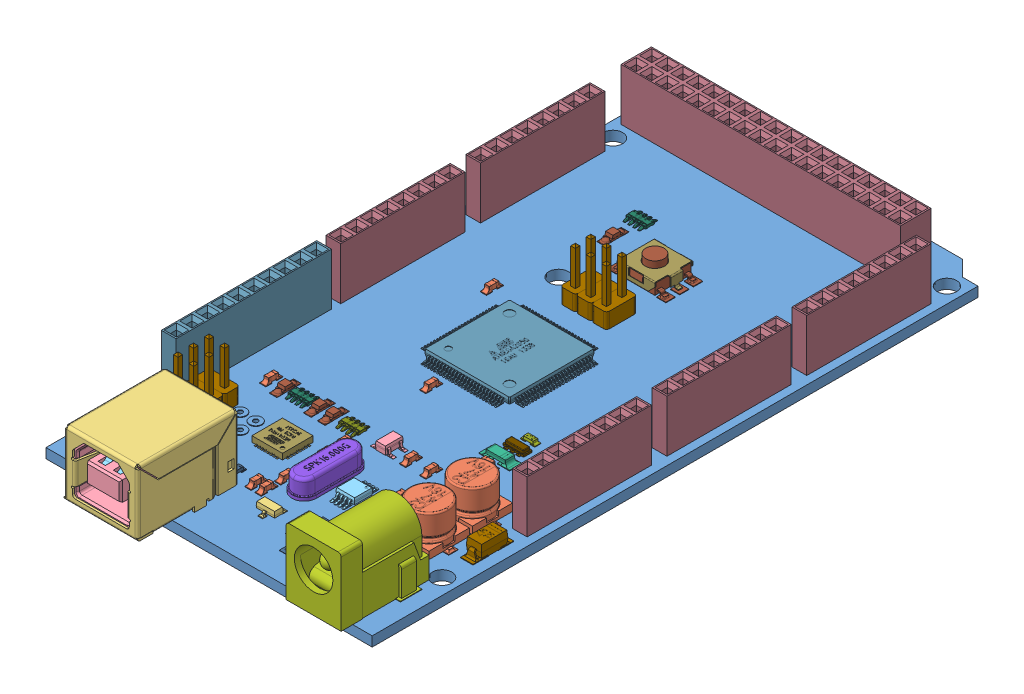
SolidWorks assembly User Library-arduino_MEGA2650-1, configuration Default. Lengths in mm.
Overall size (53.34 15.25 107.95).
66 component instances, 32 part files, 0 mates.
Components (placement in the parent):
- User Library-arduino_MEGA2650-1_MEGAboard-1: User Library-arduino_MEGA2650-1_MEGAboard [Default] at origin size (53.34 1.6 101.6)
- User Library-arduino_MEGA2650-1_47uf CAP Dcase-1: User Library-arduino_MEGA2650-1_47uf CAP Dcase [Default] at (-9.144 0 -18.415) x (0 0 -1) z (1 0 0) size (6.6 5.81 8)
- User Library-arduino_MEGA2650-1_USB SHELL-1: User Library-arduino_MEGA2650-1_USB SHELL [Default] at (-38.02 0.43 6.35) size (13.72 15.2 16.51)
- User Library-arduino_MEGA2650-1_USB core-1: User Library-arduino_MEGA2650-1_USB core [Default] at (-38.02 0.43 6.35) size (11.3 10.68 15.75)
- User Library-arduino_MEGA2650-1_usb top contact-1: User Library-arduino_MEGA2650-1_usb top contact [Default] at (-36.77 6.52 5.97) size (1 9.67 13.76)
- User Library-arduino_MEGA2650-1_usb btm contact-1: User Library-arduino_MEGA2650-1_usb btm contact [Default] at (-36.77 4.84 5.97) size (1 6.84 11.76)
- User Library-arduino_MEGA2650-1_usb btm contact-2: User Library-arduino_MEGA2650-1_usb btm contact [Default] at (-39.27 4.84 5.97) size (1 6.84 11.76)
- User Library-arduino_MEGA2650-1_usb top contact-2: User Library-arduino_MEGA2650-1_usb top contact [Default] at (-39.27 6.52 5.97) size (1 9.67 13.76)
- User Library-arduino_MEGA2650-1_power jack-1: User Library-arduino_MEGA2650-1_power jack [Default] at (-7.675 0 1.905) size (11.2 15.2 15.9)
- User Library-arduino_MEGA2650-1_47uf CAP Dcase-2: User Library-arduino_MEGA2650-1_47uf CAP Dcase [Default] at (-9.144 0 -25.527) x (0 0 -1) z (1 0 0) size (6.6 5.81 8)
- User Library-arduino_MEGA2650-1_crystal-1: User Library-arduino_MEGA2650-1_crystal [Default] at (-26.035 0 -18.415) x (1 0 0) z (0 0 -1) size (4 5 11)
- User Library-arduino_MEGA2650-1_2pin_header__02-1: User Library-arduino_MEGA2650-1_2pin_header__02 [Default] at (-46.23 0 -15.75) size (5 11.75 2.54)
- User Library-arduino_MEGA2650-1_reg-1: User Library-arduino_MEGA2650-1_reg [Default] at (-17.78 0 -8.636) size (6.5 1.69 8.3)
- User Library-arduino_MEGA2650-1_led-1: User Library-arduino_MEGA2650-1_led [Default] at (-34.29 0 -27.94) x (0 0 1) z (-1 0 0) size (4 0.9 1.55)
- User Library-arduino_MEGA2650-1_2pin_header__02-2: User Library-arduino_MEGA2650-1_2pin_header__02 [Default] at (-30.43 0 -64.91) x (0 0 1) z (-1 0 0) size (5 11.75 2.54)
- User Library-arduino_MEGA2650-1_2pin_header__02-3: User Library-arduino_MEGA2650-1_2pin_header__02 [Default] at (-27.89 0 -64.91) x (0 0 1) z (-1 0 0) size (5 11.75 2.54)
- User Library-arduino_MEGA2650-1_2pin_header__02-4: User Library-arduino_MEGA2650-1_2pin_header__02 [Default] at (-25.35 0 -64.91) x (0 0 1) z (-1 0 0) size (5 11.75 2.54)
- User Library-arduino_MEGA2650-1_2pin_header__02-5: User Library-arduino_MEGA2650-1_2pin_header__02 [Default] at (-46.23 0 -18.29) size (5 11.75 2.54)
- User Library-arduino_MEGA2650-1_2pin_header__02-6: User Library-arduino_MEGA2650-1_2pin_header__02 [Default] at (-46.23 0 -20.83) size (5 11.75 2.54)
- User Library-arduino_MEGA2650-1_atmega16u2-1: User Library-arduino_MEGA2650-1_atmega16u2 [Default] at (-34.671 0.06 -20) x (1 0 0) z (0 0 -1) size (5.5 1.01 5.5)
- User Library-arduino_MEGA2650-1_led-2: User Library-arduino_MEGA2650-1_led [Default] at (-36.576 0 -27.94) x (0 0 -1) z (1 0 0) size (4 0.9 1.55)
- User Library-arduino_MEGA2650-1_led-3: User Library-arduino_MEGA2650-1_led [Default] at (-42.164 0 -27.94) x (0 0 1) z (-1 0 0) size (4 0.9 1.55)
- User Library-arduino_MEGA2650-1_led-4: User Library-arduino_MEGA2650-1_led [Default] at (-36.83 0 -76.2) x (0 0 1) z (-1 0 0) size (4 0.9 1.55)
- User Library-arduino_MEGA2650-1_8 PORT HEADER-1: User Library-arduino_MEGA2650-1_8 PORT HEADER [Default] at (-50.8 0 -45.72) x (0 0 -1) z (1 0 0) size (20.32 10.51 2.41)
- User Library-arduino_MEGA2650-1_8 PORT HEADER-2: User Library-arduino_MEGA2650-1_8 PORT HEADER [Default] at (-2.54 0 -27.94) x (0 0 -1) z (1 0 0) size (20.32 10.51 2.41)
- User Library-arduino_MEGA2650-1_8 PORT HEADER-3: User Library-arduino_MEGA2650-1_8 PORT HEADER [Default] at (-2.54 0 -50.8) x (0 0 -1) z (1 0 0) size (20.32 10.51 2.41)
- User Library-arduino_MEGA2650-1_10 PORT HEADER-1: User Library-arduino_MEGA2650-1_10 PORT HEADER [Default] at (-50.8 0 -18.796) x (0 0 -1) z (1 0 0) size (25.4 10.51 2.41)
- User Library-arduino_MEGA2650-1_102 RESISTOR PACK-1: User Library-arduino_MEGA2650-1_102 RESISTOR PACK [Default] at (-36.83 0 -80.645) size (3.2 0.51 3)
- User Library-arduino_MEGA2650-1_102 RESISTOR PACK-2: User Library-arduino_MEGA2650-1_102 RESISTOR PACK [Default] at (-39.37 0 -27.94) size (3.2 0.51 3)
- User Library-arduino_MEGA2650-1_103 RESISTOR PACK-1: User Library-arduino_MEGA2650-1_103 RESISTOR PACK [Default] at (-31.115 0 -27.94) size (3.2 0.51 3)
- User Library-arduino_MEGA2650-1_220 RESISTOR PACK-1: User Library-arduino_MEGA2650-1_220 RESISTOR PACK [Default] at (-37.084 0 -12.065) size (3.2 0.51 3)
- User Library-arduino_MEGA2650-1_16mhz crystal - measured-1: User Library-arduino_MEGA2650-1_16mhz crystal - measured [Default] at (-14.605 0 -38.354) size (3.4 0.8 2)
- User Library-arduino_MEGA2650-1_PADS001-1: User Library-arduino_MEGA2650-1_PADS001 [Default] at (-39.878 0.1 -18.288) x (-1 0 0) z (0 0 1) size (4.54 0.1 4.54)
- User Library-arduino_MEGA2650-1_603 cap on pad-1: User Library-arduino_MEGA2650-1_603 cap on pad [Default] at (-44.45 0 -27.94) x (0 0 -1) z (1 0 0) size (2.76 0.91 1.02)
- User Library-arduino_MEGA2650-1_ssot3-1: User Library-arduino_MEGA2650-1_ssot3 [Default] at (-25.908 0 -9.144) x (-1 0 0) z (0 0 -1) size (3 1.13 3.09)
- User Library-arduino_MEGA2650-1_603 cap on pad-2: User Library-arduino_MEGA2650-1_603 cap on pad [Default] at (-29.337 0 -24.765) x (0 0 1) z (-1 0 0) size (2.76 0.91 1.02)
- User Library-arduino_MEGA2650-1_603 cap on pad-3: User Library-arduino_MEGA2650-1_603 cap on pad [Default] at (-30.988 0 -12.065) x (0 0 -1) z (1 0 0) size (2.76 0.91 1.02)
- User Library-arduino_MEGA2650-1_lmv358-1: User Library-arduino_MEGA2650-1_lmv358 [Default] at (-25.146 0 -27.94) size (3.7 1.4 2.9)
- User Library-arduino_MEGA2650-1_603 cap on pad-4: User Library-arduino_MEGA2650-1_603 cap on pad [Default] at (-17.653 0 -14.351) size (2.76 0.91 1.02)
- User Library-arduino_MEGA2650-1_603 cap on pad-5: User Library-arduino_MEGA2650-1_603 cap on pad [Default] at (-29.337 0 -12.065) x (0 0 1) z (-1 0 0) size (2.76 0.91 1.02)
- User Library-arduino_MEGA2650-1_603 cap on pad-6: User Library-arduino_MEGA2650-1_603 cap on pad [Default] at (-29.337 0 -21.59) x (0 0 1) z (-1 0 0) size (2.76 0.91 1.02)
- User Library-arduino_MEGA2650-1_603 cap on pad-7: User Library-arduino_MEGA2650-1_603 cap on pad [Default] at (-29.337 0 -15.24) x (0 0 1) z (-1 0 0) size (2.76 0.91 1.02)
- User Library-arduino_MEGA2650-1_603 cap on pad-8: User Library-arduino_MEGA2650-1_603 cap on pad [Default] at (-42.291 0 -12.065) x (0 0 1) z (-1 0 0) size (2.76 0.91 1.02)
- User Library-arduino_MEGA2650-1_lp2985dgkr-1: User Library-arduino_MEGA2650-1_lp2985dgkr [Default] at (-21.336 0 -18.415) x (0 0 -1) z (1 0 0) size (5.85 1.1 3)
- User Library-arduino_MEGA2650-1_cd1206 diode-1: User Library-arduino_MEGA2650-1_cd1206 diode [Default] at (-14.605 0 -35.56) x (0 0 1) z (-1 0 0) size (2.09 0.96 5)
- User Library-arduino_MEGA2650-1_cd1206 diode-2: User Library-arduino_MEGA2650-1_cd1206 diode [Default] at (-46.228 0 -13.081) x (0 0 1) z (-1 0 0) size (2.09 0.96 5)
- User Library-arduino_MEGA2650-1_603 resistor-1: User Library-arduino_MEGA2650-1_603 resistor [Default] at (-29.337 0 -18.415) x (0 0 1) z (-1 0 0) size (2.36 0.62 1.03)
- User Library-arduino_MEGA2650-1_blm21-1: User Library-arduino_MEGA2650-1_blm21 [Default] at (-45.085 0 -8.255) x (0 0 -1) z (1 0 0) size (2.78 0.95 1.32)
- User Library-arduino_MEGA2650-1_m7 diode-1: User Library-arduino_MEGA2650-1_m7 diode [Default] at (-2.794 0 -21.59) x (0 0 -1) z (1 0 0) size (6.66 2.35 2.5)
- User Library-arduino_MEGA2650-1_MLC0603-1: User Library-arduino_MEGA2650-1_MLC0603 [Default] at (-34.29 0 -12.065) x (0 0 -1) z (1 0 0) size (2.36 0.6 1.03)
- User Library-arduino_MEGA2650-1_MLC0603-2: User Library-arduino_MEGA2650-1_MLC0603 [Default] at (-39.878 0 -12.065) x (0 0 -1) z (1 0 0) size (2.36 0.6 1.03)
- User Library-arduino_MEGA2650-1_RESET CORE-1: User Library-arduino_MEGA2650-1_RESET CORE [Default] at (-27.94 0.1 -74.168) x (0 0 1) z (-1 0 0) size (6.2 3.1 9.6)
- User Library-arduino_MEGA2650-1_RESET-1: User Library-arduino_MEGA2650-1_RESET [Default] at (-27.94 0.1 -74.168) size (7.3 2 6.2)
- User Library-arduino_MEGA2650-1_8 PORT HEADER-4: User Library-arduino_MEGA2650-1_8 PORT HEADER [Default] at (-2.54 0 -73.66) x (0 0 -1) z (1 0 0) size (20.32 10.51 2.41)
- User Library-arduino_MEGA2650-1_8 PORT HEADER-5: User Library-arduino_MEGA2650-1_8 PORT HEADER [Default] at (-50.8 0 -68.58) x (0 0 -1) z (1 0 0) size (20.32 10.51 2.41)
- User Library-arduino_MEGA2650-1_603 cap on pad-9: User Library-arduino_MEGA2650-1_603 cap on pad [Default] at (-21.59 0 -27.94) x (0 0 1) z (-1 0 0) size (2.76 0.91 1.02)
- User Library-arduino_MEGA2650-1_603 cap on pad-10: User Library-arduino_MEGA2650-1_603 cap on pad [Default] at (-18.288 0 -27.94) x (0 0 1) z (-1 0 0) size (2.76 0.91 1.02)
- User Library-arduino_MEGA2650-1_103 RESISTOR PACK-2: User Library-arduino_MEGA2650-1_103 RESISTOR PACK [Default] at (-16.51 0 -18.415) size (3.2 0.51 3)
- User Library-arduino_MEGA2650-1_603 cap on pad-11: User Library-arduino_MEGA2650-1_603 cap on pad [Default] at (-17.145 0 -21.59) x (0 0 -1) z (1 0 0) size (2.76 0.91 1.02)
- User Library-arduino_MEGA2650-1_603 cap on pad-12: User Library-arduino_MEGA2650-1_603 cap on pad [Default] at (-39.37 0 -58.928) x (0 0 1) z (-1 0 0) size (2.76 0.91 1.02)
- User Library-arduino_MEGA2650-1_603 cap on pad-13: User Library-arduino_MEGA2650-1_603 cap on pad [Default] at (-14.605 0 -33.528) size (2.76 0.91 1.02)
- User Library-arduino_MEGA2650-1_603 resistor-2: User Library-arduino_MEGA2650-1_603 resistor [Default] at (-14.605 0 -40.513) x (-1 0 0) z (0 0 -1) size (2.36 0.62 1.03)
- User Library-arduino_MEGA2650-1_603 cap on pad-14: User Library-arduino_MEGA2650-1_603 cap on pad [Default] at (-7.112 0 -38.608) x (0 0 1) z (-1 0 0) size (2.76 0.91 1.02)
- User Library-arduino_MEGA2650-1_603 cap on pad-15: User Library-arduino_MEGA2650-1_603 cap on pad [Default] at (-30.4038 0 -40.0558) x (0 0 1) z (-1 0 0) size (2.76 0.91 1.02)
- User Library-arduino_MEGA2650-1_18 X 2 ROW HEADER-1: User Library-arduino_MEGA2650-1_18 X 2 ROW HEADER [Default] at (-50.8 0 -95.25) size (45.72 10.51 4.95)
- User Library-arduino_MEGA2650-1_atmega2650-16AU-1: User Library-arduino_MEGA2650-1_atmega2650-16AU [Default] at (-28.3464 0.1 -50.8) x (0 0 1) z (-1 0 0) size (16.8 1.11 16.8)
